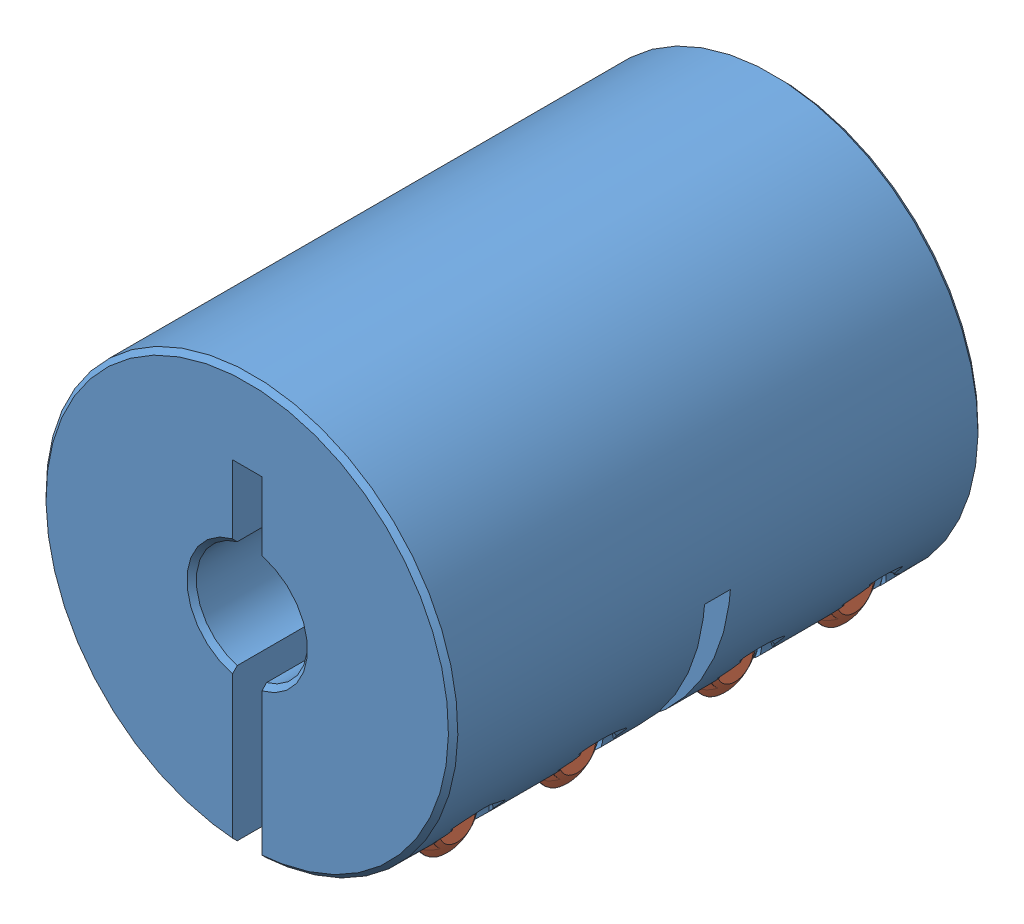
SolidWorks assembly 625100 assembly, configuration Default. Lengths in mm.
Overall size (22.23 22.2 28.58).
5 component instances, 2 part files, 0 mates.
Components (placement in the parent):
- 625100-1: 625100 [Default] at (-36.0907 -0.3474 4.9835) size (22.23 22.2 28.58)
- 632112_90128A121-1: 632112_90128A121 [Default] at (-1.3244 -7.8756 30.0025) x (0 0 -1) z (1 0 0) size (5.57 5.57 14.62)
- 632112_90128A121-2: 632112_90128A121 [Default] at (-1.3244 -7.8756 23.5255) x (0 0 -1) z (1 0 0) size (5.57 5.57 14.62)
- 632112_90128A121-3: 632112_90128A121 [Default] at (-1.3244 -7.8756 15.0165) x (0 0 -1) z (1 0 0) size (5.57 5.57 14.62)
- 632112_90128A121-4: 632112_90128A121 [Default] at (-1.3244 -7.8756 8.5395) x (0 0 -1) z (1 0 0) size (5.57 5.57 14.62)
